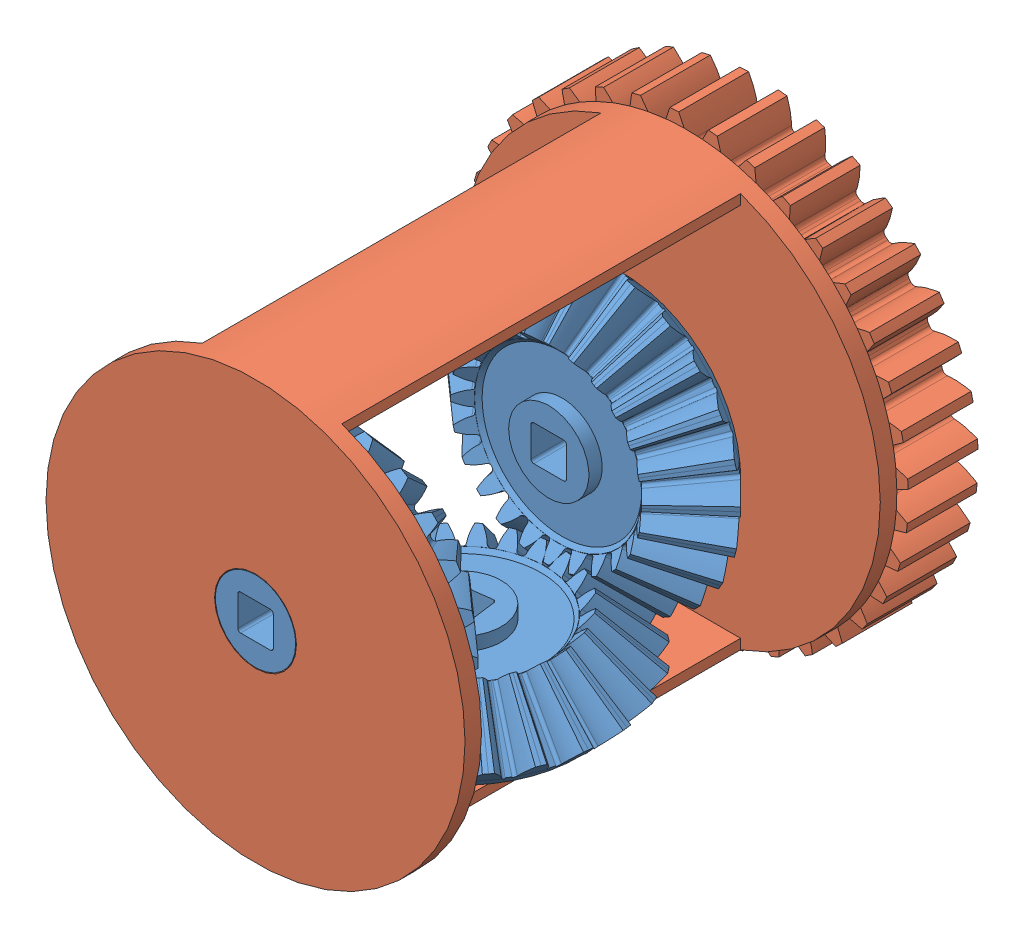
SolidWorks assembly DIFFERENTIAL-ASSY, configuration Default. Lengths in mm.
Overall size (40.19 40.19 46.78).
4 component instances, 2 part files, 0 mates.
Components (placement in the parent):
- Bevel-Gear_1-1: Bevel-Gear_1 [Default] at (0 0 7.8616) x (-1 0 0) z (0 0 -1) size (26.9 26.9 11.04)
- Differential-Housing-1: Differential-Housing [Default] at origin size (40.19 40.19 46.77)
- Bevel-Gear_1-2: Bevel-Gear_1 [Default] at (0 0 33.2102) size (26.9 26.9 11.04)
- Bevel-Gear_1-3: Bevel-Gear_1 [Default] at (0 -12.7043 20.5659) x (0.991445 0 -0.130526) z (0 -1 0) size (26.9 26.9 11.04)
